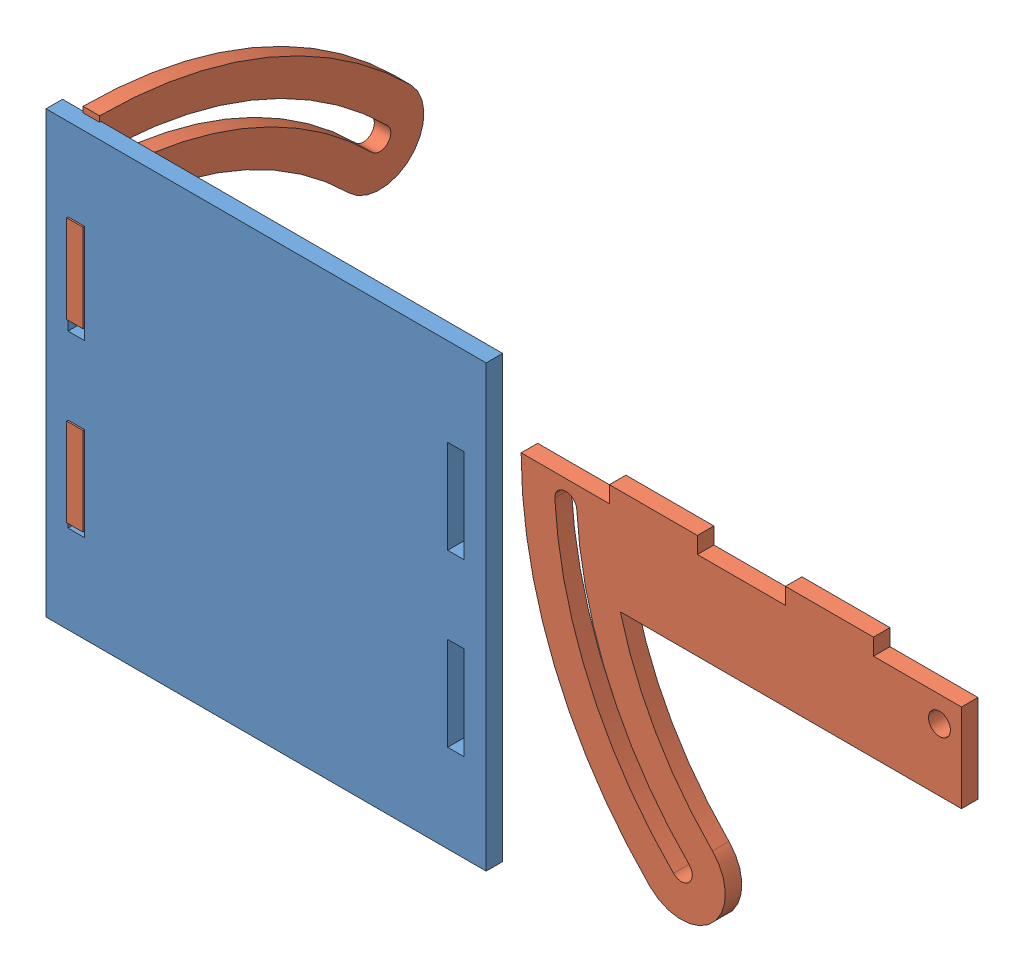
SolidWorks assembly Assem1, configuration Default. Lengths in mm.
Overall size (261.77 128.63 98.34).
3 component instances, 2 part files, 2 mates.
Components (placement in the parent):
- Plate Tray-1: Plate Tray [Default] at (-62.2422 -78.101 127) size (127 127 4.76)
- Tray Side-1: Tray Side [Default] at (72.5245 18.1897 124.6187) size (127.05 98.34 4.76)
- Tray Side-2: Tray Side [Default] at (-51.1297 65.9896 100.9956) x (0 -1 0) z (-1 0 0) size (127.05 98.34 4.76)
Mates (geometry in assembly coordinates):
- Coincident1: coincident anti-aligned: plane of Plate Tray-1 through (-55.8922 39.0148 131.7625) normal (1 0 0); plane of Tray Side-2 through (-55.8922 -61.0104 127.4287) normal (-1 0 0)
- Coincident2: coincident anti-aligned: plane of Plate Tray-1 through (-55.8922 -10.2104 131.7625) normal (0 -1 0); plane of Tray Side-2 through (-55.8922 -10.2104 127.4287) normal (0 1 0)
